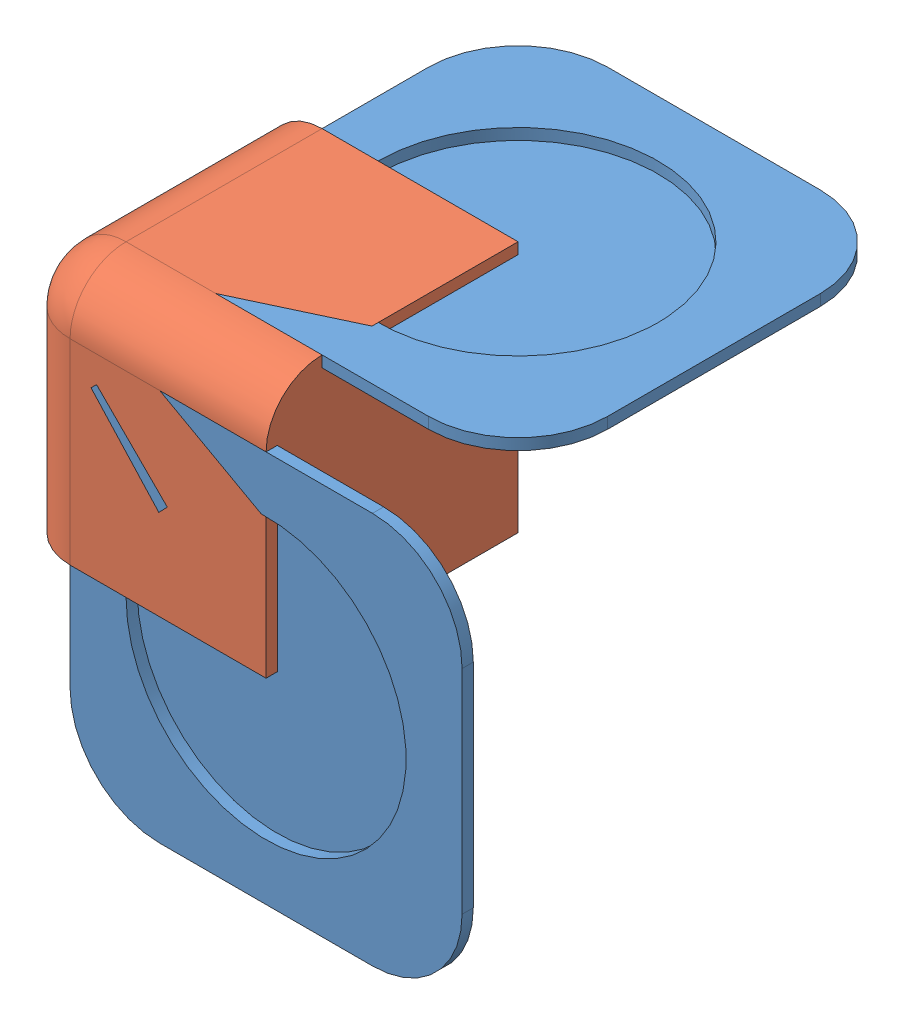
SolidWorks assembly Assem1, configuration Default. Lengths in mm.
Overall size (80 80 80).
7 component instances, 2 part files, 24 mates.
Components (placement in the parent):
- Part1-2: Part1 [Default] at (-30.6739 21.7182 43.0775) x (0 0 -1) z (0 1 0) size (70 4 70)
- Part1-7: Part1 [Default] at (12.3261 21.7182 86.0775) x (0 1 0) z (1 0 0) size (70 4 70)
- Part1-8: Part1 [Default] at (55.3261 21.7182 43.0775) x (0 1 0) z (0 0 -1) size (70 4 70) (hidden)
- Part1-9: Part1 [Default] at (12.3261 21.7182 0.0775) x (-1 0 0) z (0 -1 0) size (70 4 70) (hidden)
- Part1-10: Part1 [Default] at (12.3261 64.7182 43.0775) x (0 0 -1) z (1 0 0) size (70 4 70)
- Part1-11: Part1 [Default] at (12.3261 -21.2818 43.0775) x (-1 0 0) z (0 0 1) size (70 4 70) (hidden)
- 45cube-1: 45cube [Default] at (-32.6739 44.2182 65.5775) size (45 45 45)
Mates (geometry in assembly coordinates):
- Coincident8: coincident: moEndPointRef_w of ?; moEndPointRef_w of Part1-2
- Coincident9: coincident: moEndPointRef_w of ?; moEndPointRef_w of ?
- Coincident10: coincident: moEndPointRef_w of ?; moEndPointRef_w of ?
- Coincident11: coincident: moEndPointRef_w of ?; moEndPointRef_w of ?
- Coincident12: coincident: moEndPointRef_w of ?; moEndPointRef_w of ?
- Distance1: distance = 8 mm anti-aligned: plane of Part1-2 through (-32.6739 -13.2818 78.0775) normal (0 0 1); plane of Part1-7 through (12.3261 21.7182 86.0775) normal (0 0 -1)
- Distance2: distance = 10 mm aligned: plane of Part1-7 through (-22.6739 -13.2818 88.0775) normal (-1 0 0); plane of Part1-2 through (-32.6739 21.7182 43.0775) normal (-1 0 0)
- Coincident17: coincident aligned: plane of Part1-2 through (-32.6739 56.7182 78.0775) normal (0 1 0); plane of Part1-7 through (-22.6739 56.7182 88.0775) normal (0 1 0)
- Distance3: distance = 8 mm anti-aligned: plane of Part1-7 through (47.3261 -13.2818 88.0775) normal (1 0 0); plane of Part1-8 through (55.3261 21.7182 43.0775) normal (-1 0 0)
- Coincident19: coincident aligned: plane of Part1-7 through (-22.6739 56.7182 88.0775) normal (0 1 0); plane of Part1-8 through (57.3261 56.7182 78.0775) normal (0 1 0)
- Distance4: distance = 8 mm anti-aligned: plane of Part1-7 through (12.3261 21.7182 86.0775) normal (0 0 -1); plane of Part1-8 through (57.3261 -13.2818 78.0775) normal (0 0 1)
- Distance6: distance = 86 mm anti-aligned: plane of Part1-7 through (12.3261 21.7182 86.0775) normal (0 0 -1); plane of Part1-9 through (12.3261 21.7182 0.0775) normal (0 0 1)
- Coincident23: coincident aligned: plane of Part1-7 through (-22.6739 56.7182 88.0775) normal (0 1 0); plane of Part1-9 through (47.3261 56.7182 -1.9225) normal (0 1 0)
- Coincident24: coincident: line of Part1-7 through (47.3261 2.7182 88.0775) axis (0 1 0); plane of Part1-9 through (47.3261 56.7182 -1.9225) normal (1 0 0)
- Coincident25: coincident: plane of Part1-2 through (-16.6739 21.7182 43.0775) normal (-1 0 0); plane of ? through (-16.6739 56.7182 -11.9225) normal (-1 0 0)
- Coincident26: coincident: plane of Part1-2 through (-16.6739 56.7182 78.0775) normal (0 1 0); plane of ? through (28.3261 56.7182 33.0775) normal (0 1 0)
- Coincident28: coincident aligned: plane of Part1-2 through (-16.6739 -13.2818 78.0775) normal (0 0 1); plane of ? through (-16.6739 56.7182 78.0775) normal (0 0 1)
- Distance10: distance = 8 mm anti-aligned: plane of Part1-7 through (12.3261 21.7182 86.0775) normal (0 0 -1); plane of Part1-11 through (47.3261 -23.2818 78.0775) normal (0 0 1)
- Distance11: distance = 8 mm anti-aligned: plane of Part1-11 through (-22.6739 -23.2818 8.0775) normal (-1 0 0); plane of Part1-2 through (-30.6739 21.7182 43.0775) normal (1 0 0)
- Coincident40: coincident aligned: plane of Part1-2 through (-32.6739 21.7182 43.0775) normal (-1 0 0); plane of 45cube-1 through (-32.6739 44.2182 65.5775) normal (-1 0 0)
- Coincident41: coincident aligned: plane of Part1-7 through (12.3261 21.7182 88.0775) normal (0 0 1); plane of 45cube-1 through (12.3261 66.7182 88.0775) normal (0 0 1)
- Coincident42: coincident aligned: plane of Part1-10 through (12.3261 66.7182 43.0775) normal (0 1 0); plane of 45cube-1 through (12.3261 66.7182 88.0775) normal (0 1 0)
- Distance13: distance = 8 mm anti-aligned: plane of Part1-10 through (-22.6739 66.7182 78.0775) normal (0 0 1); plane of Part1-7 through (12.3261 21.7182 86.0775) normal (0 0 -1)
- Distance14: distance = 8 mm anti-aligned: plane of Part1-10 through (-22.6739 66.7182 78.0775) normal (-1 0 0); plane of Part1-2 through (-30.6739 21.7182 43.0775) normal (1 0 0)
